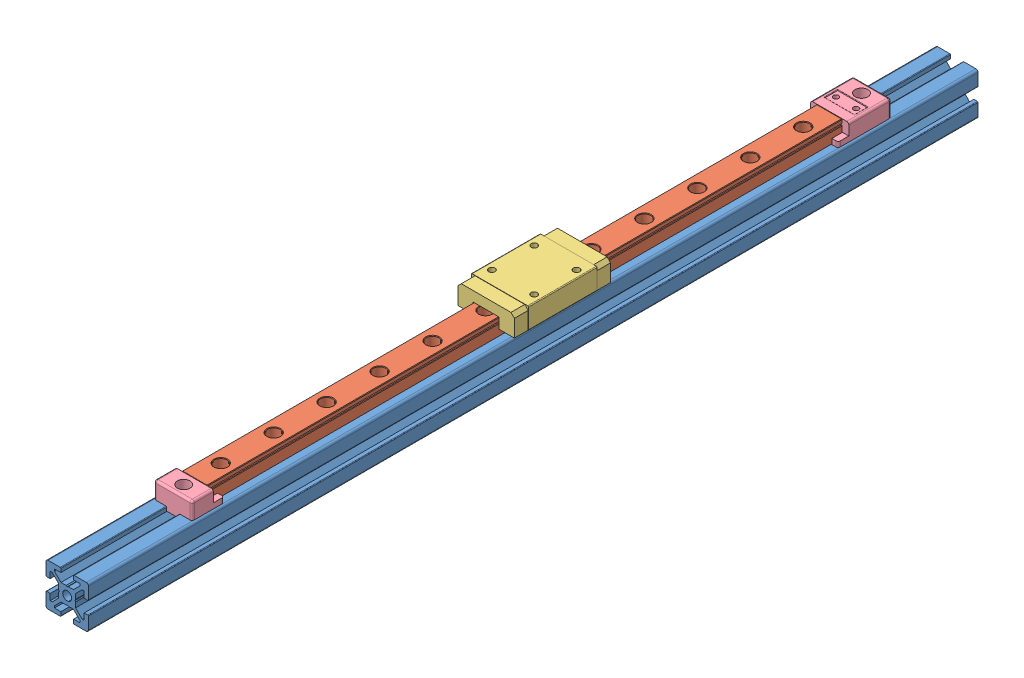
SolidWorks assembly assembled_stops, configuration Default. Lengths in mm.
Overall size (27 33 420).
5 component instances, 4 part files, 12 mates.
Components (placement in the parent):
- misumi-HFSB5-2020-extrusion-1: misumi-HFSB5-2020-extrusion [420mm] at origin size (20 20 420)
- mgn12h_linear_rail-1: mgn12h_linear_rail [300mm] at (0 14 -360) x (0 0 1) z (-1 0 0) size (300 8 12)
- mgn12h_linear_rail_cartridge-1: mgn12h_linear_rail_cartridge [Default] at (0 23 -220.4852) x (0 0 -1) z (1 0 0) size (45.4 10 27)
- stop-1: stop [EndstopHolder] at (0 10 0) x (1 0 0) z (0 1 0) size (18 25 9.9)
- stop-2: stop [CarriageStop] at (0 10 -420) x (-1 0 0) z (0 1 0) size (18 15 9.9)
Mates (geometry in assembly coordinates):
- Coincident1: coincident anti-aligned: plane of misumi-HFSB5-2020-extrusion-1 through (9 10 -420) normal (0 1 0); plane of mgn12h_linear_rail-1 through (6 10 -60) normal (0 -1 0)
- Coincident2: coincident anti-aligned: plane of misumi-HFSB5-2020-extrusion-1 through (0 0 0) normal (1 0 0); plane of mgn12h_linear_rail-1 through (0 14 -360) normal (-1 0 0)
- Distance1: distance = 60 mm aligned: plane of mgn12h_linear_rail-1 through (0 14 -60) normal (0 0 1); plane of misumi-HFSB5-2020-extrusion-1 through (-9 9 0) normal (0 0 1)
- Coincident4: coincident anti-aligned: plane of mgn12h_linear_rail-1 through (6 18 -60) normal (0 1 0); plane of mgn12h_linear_rail_cartridge-1 through (6 18 -204.2852) normal (0 -1 0)
- Coincident5: coincident anti-aligned: plane of mgn12h_linear_rail-1 through (0 14 -360) normal (-1 0 0); plane of mgn12h_linear_rail_cartridge-1 through (0 23 -220.4852) normal (1 0 0)
- InPlace1: in place: plane of misumi-HFSB5-2020-extrusion-1 through (9 10 -420) normal (0 1 0); plane of stop-1 through (0 10 0) normal (0 1 0); moOrthogonalPlaneRef_w of misumi-HFSB5-2020-extrusion-1 through (9 10 -420) normal (0 1 0); plane of stop-1 through (0 10 0) normal (0 0 -1); plane of misumi-HFSB5-2020-extrusion-1 through (9 10 -420) normal (0 1 0); line of stop-1 through (-55 0 10) axis (0 1 0); plane of misumi-HFSB5-2020-extrusion-1 through (9 10 -420) normal (0 1 0); unknown of stop-1
- Coincident6: coincident aligned: plane of misumi-HFSB5-2020-extrusion-1; plane of stop-1
- Coincident7: coincident aligned: moOrthogonalPlaneRef_w of misumi-HFSB5-2020-extrusion-1 through (0 10 0) normal (0 0 -1); plane of stop-1 through (0 10 0) normal (0 0 -1)
- Coincident8: coincident anti-aligned: moOrthogonalPlaneRef_w of misumi-HFSB5-2020-extrusion-1 through (0 10 0) normal (-1 0 0); plane of stop-1
- Coincident10: coincident anti-aligned: plane of misumi-HFSB5-2020-extrusion-1 through (-3.3 10 -420) normal (0 1 0); plane of stop-2 through (0 10 -420) normal (0 -1 0)
- Coincident11: coincident anti-aligned: plane of stop-2; plane of assembly through (0 0 0) normal (1 0 0)
- Coincident12: coincident anti-aligned: plane of mgn12h_linear_rail-1 through (0 14 -60) normal (0 0 1); plane of stop-2 through (-6 12.5 -60) normal (0 0 -1)
